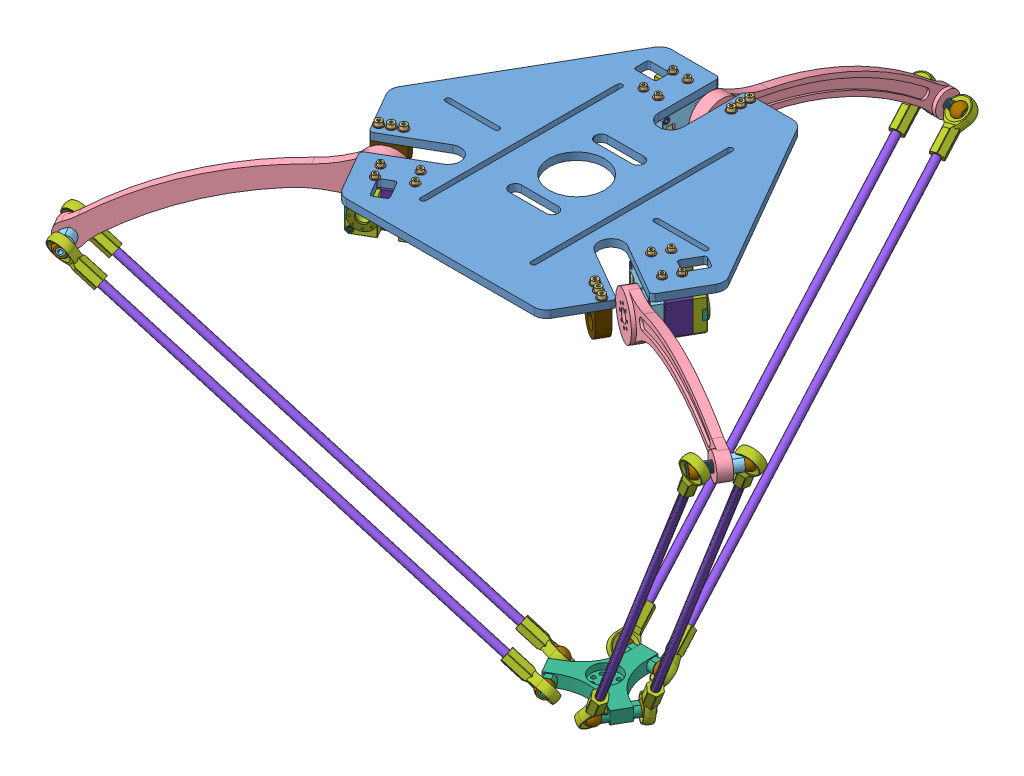
SolidWorks assembly Delta2, configuration Default. Lengths in mm.
Overall size (577.62 355.98 496.17).
140 component instances, 27 part files, 133 mates.
Components (placement in the parent):
- base_XM430-1: base_XM430 [Default] at (314.8111 1004.7421 791.2344) x (-1 0 0) z (0 1 0) size (271.39 237.71 6)
- XM430-W350-R-1: XM430-W350-R [Default] at (418.2079 990.0054 820.437) x (0 -1 0) z (-0.5 0 0.866025) size (28.5 46.5 41)
  - XM430-W350-R.step-1: XM430-W350-R.step [Default] at origin size (28.5 46.5 41)
    - Part 1.step-1: Part 1.step [Default] at (-0.4867 -0.6755 -0.5918) size (19.5 19.5 4)
    - Part 2.step-1: Part 2.step [Default] at (-0.4867 -0.6755 -0.5918) size (13.3 5.9 0.1)
    - Part 3.step-1: Part 3.step [Default] at (-0.4867 -0.6755 -0.5918) size (13.3 1.9 0.1)
    - Part 4.step-1: Part 4.step [Default] at (-0.4867 -0.6755 -0.5918) size (28.5 46.5 8.5)
    - Part 5.step-1: Part 5.step [Default] at (-0.4867 -0.6755 -0.5918) size (8 1.5 3)
    - Part 6.step-1: Part 6.step [Default] at (-0.4867 -0.6755 -0.5918) size (28.5 46.5 8.5)
    - Part 7.step-1: Part 7.step [Default] at (-0.4867 -0.6755 -0.5918) size (4 4 3.8)
    - Part 8.step-1: Part 8.step [Default] at (-0.4867 -0.6755 -0.5918) size (4 4 3.8)
    - Part 9.step-1: Part 9.step [Default] at (-0.4867 -0.6755 -0.5918) size (4 4 3.8)
    - Part 10.step-1: Part 10.step [Default] at (-0.4867 -0.6755 -0.5918) size (4 4 3.8)
    - Part 11.step-1: Part 11.step [Default] at (-0.4867 -0.6755 -0.5918) size (4 4 3.8)
    - Part 12.step-1: Part 12.step [Default] at (-0.4867 -0.6755 -0.5918) size (4 4 3.8)
    - Part 13.step-1: Part 13.step [Default] at (-0.4867 -0.6755 -0.5918) size (4 4 3.8)
    - Part 14.step-1: Part 14.step [Default] at (-0.4867 -0.6755 -0.5918) size (4 4 3.8)
    - Part 15.step-1: Part 15.step [Default] at (-0.4867 -0.6755 -0.5918) size (19.5 19.5 2)
    - Part 16.step-1: Part 16.step [Default] at (-0.4867 -0.6755 -0.5918) size (28.5 46.5 17)
- bearing_block _xm-1: bearing_block _xm [Default] at (416.3014 973.7421 876.388) x (-0.866025 0 -0.5) z (0.5 0 -0.866025) size (22.5 25 10)
- single row radial ball bearing_is-1: single row radial ball bearing_is [IS 6455 SR - 18-8-S] at (406.8111 990.4921 862.8258) x (0.85015 0.190598 0.490834) z (-0.5 0 0.866025) size (16 16 4)
- single row radial ball bearing_is-2: single row radial ball bearing_is [IS 6455 SR - 18-8-S] at (330.8111 990.4921 675.7644) x (0 0.190598 -0.981668) z (1 0 0) size (16 16 4)
- single row radial ball bearing_is-3: single row radial ball bearing_is [IS 6455 SR - 18-8-S] at (206.8112 990.4921 835.113) x (-0.85015 0.190598 0.490834) z (-0.5 0 -0.866025) size (16 16 4)
- bearing_block _xm-2: bearing_block _xm [Default] at (337.8111 973.7421 660.7644) x (0 0 1) z (-1 0 0) size (22.5 25 10)
- bearing_block _xm-3: bearing_block _xm [Default] at (190.3208 973.7421 836.5508) x (0.866025 0 -0.5) z (0.5 0 0.866025) size (22.5 25 10)
- XM430-W350-R-2: XM430-W350-R [Default] at (288.4029 990.0054 687.0889) x (0 -1 0) z (1 0 0) size (28.5 46.5 41)
  - XM430-W350-R.step-1: XM430-W350-R.step [Default] at origin size (28.5 46.5 41)
    - Part 1.step-1: Part 1.step [Default] at (-0.4867 -0.6755 -0.5918) size (19.5 19.5 4)
    - Part 2.step-1: Part 2.step [Default] at (-0.4867 -0.6755 -0.5918) size (13.3 5.9 0.1)
    - Part 3.step-1: Part 3.step [Default] at (-0.4867 -0.6755 -0.5918) size (13.3 1.9 0.1)
    - Part 4.step-1: Part 4.step [Default] at (-0.4867 -0.6755 -0.5918) size (28.5 46.5 8.5)
    - Part 5.step-1: Part 5.step [Default] at (-0.4867 -0.6755 -0.5918) size (8 1.5 3)
    - Part 6.step-1: Part 6.step [Default] at (-0.4867 -0.6755 -0.5918) size (28.5 46.5 8.5)
    - Part 7.step-1: Part 7.step [Default] at (-0.4867 -0.6755 -0.5918) size (4 4 3.8)
    - Part 8.step-1: Part 8.step [Default] at (-0.4867 -0.6755 -0.5918) size (4 4 3.8)
    - Part 9.step-1: Part 9.step [Default] at (-0.4867 -0.6755 -0.5918) size (4 4 3.8)
    - Part 10.step-1: Part 10.step [Default] at (-0.4867 -0.6755 -0.5918) size (4 4 3.8)
    - Part 11.step-1: Part 11.step [Default] at (-0.4867 -0.6755 -0.5918) size (4 4 3.8)
    - Part 12.step-1: Part 12.step [Default] at (-0.4867 -0.6755 -0.5918) size (4 4 3.8)
    - Part 13.step-1: Part 13.step [Default] at (-0.4867 -0.6755 -0.5918) size (4 4 3.8)
    - Part 14.step-1: Part 14.step [Default] at (-0.4867 -0.6755 -0.5918) size (4 4 3.8)
    - Part 15.step-1: Part 15.step [Default] at (-0.4867 -0.6755 -0.5918) size (19.5 19.5 2)
    - Part 16.step-1: Part 16.step [Default] at (-0.4867 -0.6755 -0.5918) size (28.5 46.5 17)
- XM430-W350-R-3: XM430-W350-R [Default] at (237.8225 990.0054 866.1773) x (0 -1 0) z (-0.5 0 -0.866025) size (28.5 46.5 41)
  - XM430-W350-R.step-1: XM430-W350-R.step [Default] at origin size (28.5 46.5 41)
    - Part 1.step-1: Part 1.step [Default] at (-0.4867 -0.6755 -0.5918) size (19.5 19.5 4)
    - Part 2.step-1: Part 2.step [Default] at (-0.4867 -0.6755 -0.5918) size (13.3 5.9 0.1)
    - Part 3.step-1: Part 3.step [Default] at (-0.4867 -0.6755 -0.5918) size (13.3 1.9 0.1)
    - Part 4.step-1: Part 4.step [Default] at (-0.4867 -0.6755 -0.5918) size (28.5 46.5 8.5)
    - Part 5.step-1: Part 5.step [Default] at (-0.4867 -0.6755 -0.5918) size (8 1.5 3)
    - Part 6.step-1: Part 6.step [Default] at (-0.4867 -0.6755 -0.5918) size (28.5 46.5 8.5)
    - Part 7.step-1: Part 7.step [Default] at (-0.4867 -0.6755 -0.5918) size (4 4 3.8)
    - Part 8.step-1: Part 8.step [Default] at (-0.4867 -0.6755 -0.5918) size (4 4 3.8)
    - Part 9.step-1: Part 9.step [Default] at (-0.4867 -0.6755 -0.5918) size (4 4 3.8)
    - Part 10.step-1: Part 10.step [Default] at (-0.4867 -0.6755 -0.5918) size (4 4 3.8)
    - Part 11.step-1: Part 11.step [Default] at (-0.4867 -0.6755 -0.5918) size (4 4 3.8)
    - Part 12.step-1: Part 12.step [Default] at (-0.4867 -0.6755 -0.5918) size (4 4 3.8)
    - Part 13.step-1: Part 13.step [Default] at (-0.4867 -0.6755 -0.5918) size (4 4 3.8)
    - Part 14.step-1: Part 14.step [Default] at (-0.4867 -0.6755 -0.5918) size (4 4 3.8)
    - Part 15.step-1: Part 15.step [Default] at (-0.4867 -0.6755 -0.5918) size (19.5 19.5 2)
    - Part 16.step-1: Part 16.step [Default] at (-0.4867 -0.6755 -0.5918) size (28.5 46.5 17)
- plain washer (type a)_is-1: plain washer (type a)_is [IS 2016 A- 3.4] at (199.316 1010.7421 837.1309) x (-0.701639 0 0.712533) z (0.712533 0 0.701639) size (7 0.5 7)
- plain washer (type a)_is-2: plain washer (type a)_is [IS 2016 A- 3.4] at (205.8112 1010.7421 833.3809) x (-0.554786 0 0.831993) z (0.831993 0 0.554786) size (7 0.5 7)
- plain washer (type a)_is-4: plain washer (type a)_is [IS 2016 A- 3.4] at (212.3063 1010.7421 829.6309) x (-0.362387 0 0.932028) z (0.932028 0 0.362387) size (7 0.5 7)
- plain washer (type a)_is-8: plain washer (type a)_is [IS 2016 A- 3.4] at (399.3159 1010.7421 860.8079) x (-0.133791 0 0.99101) z (0.99101 0 0.133791) size (7 0.5 7)
- plain washer (type a)_is-11: plain washer (type a)_is [IS 2016 A- 3.4] at (412.3063 1010.7421 868.3079) x (0.106727 0 0.994288) z (0.994288 0 -0.106727) size (7 0.5 7)
- plain washer (type a)_is-13: plain washer (type a)_is [IS 2016 A- 3.4] at (405.8111 1010.7421 864.5579) x (0.327312 0 0.944916) z (0.944916 0 -0.327312) size (7 0.5 7)
- plain washer (type a)_is-15: plain washer (type a)_is [IS 2016 A- 3.4] at (332.8111 1010.7421 668.2644) x (0.502717 0 0.864451) z (0.864451 0 -0.502717) size (7 0.5 7)
- plain washer (type a)_is-17: plain washer (type a)_is [IS 2016 A- 3.4] at (332.8111 1010.7421 675.7644) x (0.623048 0 0.782184) z (0.782184 0 -0.623048) size (7 0.5 7)
- plain washer (type a)_is-19: plain washer (type a)_is [IS 2016 A- 3.4] at (332.8111 1010.7421 683.2644) x (0.69089 0 0.72296) z (0.72296 0 -0.69089) size (7 0.5 7)
- socket head cap screw_is-1: socket head cap screw_is [IS 2269 - M3 x 10-N] at (199.316 1014.2421 837.1309) x (0 -1 0) z (0.966494 0 -0.25669) size (13 5.5 5.5)
- socket head cap screw_is-2: socket head cap screw_is [IS 2269 - M3 x 10-N] at (205.8112 1014.2421 833.3809) x (0 -1 0) z (0.900802 0 -0.434231) size (13 5.5 5.5)
- socket head cap screw_is-4: socket head cap screw_is [IS 2269 - M3 x 10-N] at (212.3063 1014.2421 829.6309) x (0 -1 0) z (0.786013 0 -0.61821) size (13 5.5 5.5)
- socket head cap screw_is-6: socket head cap screw_is [IS 2269 - M3 x 10-N] at (332.8111 1014.2421 668.2644) x (0 -1 0) z (0.619181 0 -0.785248) size (13 5.5 5.5)
- socket head cap screw_is-8: socket head cap screw_is [IS 2269 - M3 x 10-N] at (332.8111 1014.2421 675.7644) x (0 -1 0) z (0.413756 0 -0.910388) size (13 5.5 5.5)
- socket head cap screw_is-10: socket head cap screw_is [IS 2269 - M3 x 10-N] at (332.8111 1014.2421 683.2644) x (0 -1 0) z (0.198717 0 -0.980057) size (13 5.5 5.5)
- socket head cap screw_is-12: socket head cap screw_is [IS 2269 - M3 x 10-N] at (412.3063 1014.2421 868.3079) x (0 -1 0) z (0.006767 0 -0.999977) size (13 5.5 5.5)
- socket head cap screw_is-14: socket head cap screw_is [IS 2269 - M3 x 10-N] at (405.8111 1014.2421 864.5579) x (0 -1 0) z (-0.138678 0 -0.990337) size (13 5.5 5.5)
- socket head cap screw_is-16: socket head cap screw_is [IS 2269 - M3 x 10-N] at (399.3159 1014.2421 860.8079) x (0 -1 0) z (-0.227212 0 -0.973845) size (13 5.5 5.5)
- plain washer (type a)_is-21: plain washer (type a)_is [IS 2016 A- 2.9] at (293.8111 1010.7421 679.7644) x (0.656619 0 0.754222) z (0.754222 0 -0.656619) size (6.5 0.5 6.5)
- plain washer (type a)_is-25: plain washer (type a)_is [IS 2016 A- 2.9] at (281.8111 1010.7421 679.7644) x (0.786991 0 0.616965) z (0.616965 0 -0.786991) size (6.5 0.5 6.5)
- plain washer (type a)_is-27: plain washer (type a)_is [IS 2016 A- 2.9] at (293.8111 1010.7421 703.7644) x (0.901488 0 0.432805) z (0.432805 0 -0.901488) size (6.5 0.5 6.5)
- plain washer (type a)_is-32: plain washer (type a)_is [IS 2016 A- 2.9] at (281.8111 1010.7421 703.7644) x (0.977829 0 0.209406) z (0.209406 0 -0.977829) size (6.5 0.5 6.5)
- plain washer (type a)_is-34: plain washer (type a)_is [IS 2016 A- 2.9] at (234.7753 1010.7421 875.5482) x (0.140812 0 -0.990036) z (-0.990036 0 -0.140812) size (6.5 0.5 6.5)
- plain washer (type a)_is-35: plain washer (type a)_is [IS 2016 A- 2.9] at (427.847 1010.7421 818.3906) x (-0.927803 0 0.373071) z (0.373071 0 0.927803) size (6.5 0.5 6.5)
- plain washer (type a)_is-36: plain washer (type a)_is [IS 2016 A- 2.9] at (228.7753 1010.7421 865.1559) x (0.324866 0 -0.94576) z (-0.94576 0 -0.324866) size (6.5 0.5 6.5)
- plain washer (type a)_is-37: plain washer (type a)_is [IS 2016 A- 2.9] at (421.847 1010.7421 828.7829) x (-0.981485 0 0.191538) z (0.191538 0 0.981485) size (6.5 0.5 6.5)
- plain washer (type a)_is-38: plain washer (type a)_is [IS 2016 A- 2.9] at (255.5599 1010.7421 863.5482) x (-0.307563 0 -0.951528) z (-0.951528 0 0.307563) size (6.5 0.5 6.5)
- plain washer (type a)_is-39: plain washer (type a)_is [IS 2016 A- 2.9] at (407.0624 1010.7421 806.3906) x (-0.670266 0 0.742121) z (0.742121 0 0.670266) size (6.5 0.5 6.5)
- plain washer (type a)_is-40: plain washer (type a)_is [IS 2016 A- 2.9] at (249.5599 1010.7421 853.1559) x (-0.075924 0 -0.997114) z (-0.997114 0 0.075924) size (6.5 0.5 6.5)
- plain washer (type a)_is-41: plain washer (type a)_is [IS 2016 A- 2.9] at (401.0624 1010.7421 816.7829) x (-0.825564 0 0.564309) z (0.564309 0 0.825564) size (6.5 0.5 6.5)
- socket head cap screw_is-38: socket head cap screw_is [IS 2269 - M2.5 x 8-N] at (293.8111 1013.7421 679.7644) x (0 -1 0) z (0.760684 0 -0.649123) size (10.5 4.5 4.5)
- socket head cap screw_is-39: socket head cap screw_is [IS 2269 - M2.5 x 8-N] at (281.8111 1013.7421 679.7644) x (0 -1 0) z (0.624723 0 -0.780846) size (10.5 4.5 4.5)
- socket head cap screw_is-41: socket head cap screw_is [IS 2269 - M2.5 x 8-N] at (293.8111 1013.7421 703.7644) x (0 -1 0) z (0.441705 0 -0.89716) size (10.5 4.5 4.5)
- socket head cap screw_is-43: socket head cap screw_is [IS 2269 - M2.5 x 8-N] at (281.8111 1013.7421 703.7644) x (0 -1 0) z (0.219073 0 -0.975708) size (10.5 4.5 4.5)
- socket head cap screw_is-45: socket head cap screw_is [IS 2269 - M2.5 x 8-N] at (228.7753 1013.7421 865.1559) x (0 -1 0) z (-0.942499 0 -0.33421) size (10.5 4.5 4.5)
- socket head cap screw_is-46: socket head cap screw_is [IS 2269 - M2.5 x 8-N] at (421.847 1013.7421 828.7829) x (0 -1 0) z (0.181815 0 0.983333) size (10.5 4.5 4.5)
- socket head cap screw_is-47: socket head cap screw_is [IS 2269 - M2.5 x 8-N] at (234.7753 1013.7421 875.5482) x (0 -1 0) z (-0.988594 0 -0.150603) size (10.5 4.5 4.5)
- socket head cap screw_is-48: socket head cap screw_is [IS 2269 - M2.5 x 8-N] at (427.847 1013.7421 818.3906) x (0 -1 0) z (0.363871 0 0.931449) size (10.5 4.5 4.5)
- socket head cap screw_is-49: socket head cap screw_is [IS 2269 - M2.5 x 8-N] at (255.5599 1013.7421 863.5482) x (0 -1 0) z (-0.954525 0 0.298131) size (10.5 4.5 4.5)
- socket head cap screw_is-50: socket head cap screw_is [IS 2269 - M2.5 x 8-N] at (407.0624 1013.7421 806.3906) x (0 -1 0) z (0.735452 0 0.677577) size (10.5 4.5 4.5)
- socket head cap screw_is-51: socket head cap screw_is [IS 2269 - M2.5 x 8-N] at (249.5599 1013.7421 853.1559) x (0 -1 0) z (-0.997816 0 0.066052) size (10.5 4.5 4.5)
- socket head cap screw_is-52: socket head cap screw_is [IS 2269 - M2.5 x 8-N] at (401.0624 1013.7421 816.7829) x (0 -1 0) z (0.556111 0 0.831108) size (10.5 4.5 4.5)
- link1-1: link1 [Default] at (418.3111 990.4921 842.9072) x (0.857298 0.141609 0.494961) z (-0.5 0 0.866025) size (227.5 42.75 10)
- link1-2: link1 [Default] at (307.8111 990.4921 675.7644) x (0 -0.393866 -0.919168) z (1 0 0) size (227.5 42.75 10)
- link1-3: link1 [Default] at (218.3112 990.4921 855.0316) x (-0.80505 -0.36859 0.464796) z (-0.5 0 -0.866025) size (227.5 42.75 10)
- custom_pin-1: custom_pin [Default] at (323.8111 912.1088 491.7643) x (0 0.588093 0.808793) z (-1 0 0) size (12 10.5 42)
- custom_pin-2: custom_pin [Default] at (49.1661 917.1684 934.2123) x (0.762742 0.473604 -0.440369) z (0.5 0 0.866025) size (12 10.5 42)
- custom_pin-3: custom_pin [Default] at (581.7183 1019.2334 955.7257) x (-0.86532 0.040344 -0.499593) z (0.5 0 -0.866025) size (12 10.5 42)
- end_effector_assembly-1: end_effector_assembly [Default] at (374.6664 654.2453 825.2104) x (-0.560777 -0.060135 0.82578) z (-0.826518 0.099627 -0.554024) size (80.52 17.97 73.66)
- KCRM-06-01-1: KCRM-06-01 [Default] at (335.3363 721.3364 868.7926) x (-0.607559 -0.609042 -0.509844) z (-0.129591 -0.557287 0.820144) size (20 40 10)
- KCRM-06-01-2: KCRM-06-01 [Default] at (86.9251 900.2377 951.1043) x (0.620597 0.729976 0.286345) z (0.027943 -0.385533 0.922271) size (20 40 10)
- lower_link-2: lower_link [Default] at (348.2662 712.0245 864.5082) x (0.620597 0.729976 0.286345) z (0.027943 -0.385533 0.922271) size (6 350 6)
- KCRM-06 -02-1: KCRM-06 -02 [Default] at (358.8452 704.4057 861.0028) x (0.156369 0.983564 -0.09028) z (0.5 0 0.866025) size (12.7 12.7 9)
- KCRM-06 -02-2: KCRM-06 -02 [Default] at (63.4161 917.1684 958.894) x (0.860886 -0.108782 -0.497033) z (0.5 0 0.866025) size (12.7 12.7 9)
- KCRM-06 -02-6: KCRM-06 -02 [Default] at (579.4683 1019.2334 959.6228) x (0.829488 -0.287402 0.478905) z (-0.5 0 0.866025) size (12.7 12.7 9)
- KCRM-06 -02-7: KCRM-06 -02 [Default] at (397.0221 704.4057 861.0028) x (-0.113028 0.991447 -0.065257) z (0.5 0 -0.866025) size (12.7 12.7 9)
- lower_link-8: lower_link [Default] at (403.5553 715.6794 864.5343) x (-0.840269 0.359936 0.405455) z (-0.244434 0.416024 -0.875886) size (6 350 6)
- KCRM-06-01-9: KCRM-06-01 [Default] at (564.9501 994.1808 951.775) x (0.874111 -0.475503 -0.099133) z (-0.041603 -0.276634 0.960074) size (20 40 10)
- KCRM-06-01-10: KCRM-06-01 [Default] at (411.5404 729.4583 868.8506) x (-0.366792 -0.077836 0.927041) z (0.794521 -0.544584 0.268634) size (20 40 10)
- KCRM-06 -02-8: KCRM-06 -02 [Default] at (328.3111 912.1088 491.7643) x (0 0.033864 -0.999426) z (1 0 0) size (12.7 12.7 9)
- KCRM-06 -02-9: KCRM-06 -02 [Default] at (394.4337 704.4057 799.3618) x (0 0.812147 0.583453) z (1 0 0) size (12.7 12.7 9)
- lower_link-9: lower_link [Default] at (392.0659 711.8434 788.3471) x (0.980998 0.167633 -0.097687) z (-0.082954 0.817538 0.569869) size (6 350 6)
- KCRM-06-01-11: KCRM-06-01 [Default] at (333.5729 895.5807 516.2415) x (0.980998 0.167633 -0.097687) z (-0.082954 0.817538 0.569869) size (20 40 10)
- KCRM-06-01-12: KCRM-06-01 [Default] at (389.1719 720.9338 774.8846) x (-0.789881 -0.57343 -0.217408) z (-0.587645 0.606339 0.535749) size (20 40 10)
- KCRM-06 -02-10: KCRM-06 -02 [Default] at (595.9683 1019.2334 931.0439) x (0.847524 -0.2056 0.489318) z (-0.5 0 0.866025) size (12.7 12.7 9)
- KCRM-06 -02-11: KCRM-06 -02 [Default] at (413.5221 704.4057 832.424) x (-0.484483 0.828876 -0.279716) z (0.5 0 -0.866025) size (12.7 12.7 9)
- lower_link-10: lower_link [Default] at (420.0553 715.6794 835.9555) x (0.866547 -0.415611 -0.276339) z (0.122047 -0.360413 0.924774) size (6 350 6)
- KCRM-06-01-13: KCRM-06-01 [Default] at (581.4501 994.1808 923.1962) x (0.866547 -0.415611 -0.276339) z (0.122047 -0.360413 0.924774) size (20 40 10)
- KCRM-06-01-14: KCRM-06-01 [Default] at (428.0404 729.4583 840.2717) x (-0.649113 0.543036 -0.532695) z (-0.5869 0.087991 0.804864) size (20 40 10)
- KCRM-06 -02-12: KCRM-06 -02 [Default] at (46.9161 917.1684 930.3152) x (0.860886 -0.108782 -0.497033) z (0.5 0 0.866025) size (12.7 12.7 9)
- KCRM-06 -02-13: KCRM-06 -02 [Default] at (342.3452 704.4057 832.424) x (-0.379043 -0.89913 0.218841) z (-0.5 0 -0.866025) size (12.7 12.7 9)
- lower_link-11: lower_link [Default] at (331.7662 712.0245 835.9294) x (0.614002 0.767175 0.185591) z (0.094464 -0.304865 0.947699) size (6 350 6)
- KCRM-06-01-15: KCRM-06-01 [Default] at (70.4251 900.2377 922.5254) x (0.614002 0.767175 0.185591) z (0.094464 -0.304865 0.947699) size (20 40 10)
- KCRM-06-01-16: KCRM-06-01 [Default] at (318.8363 721.3364 840.2137) x (-0.56569 -0.475511 -0.673709) z (-0.256742 -0.674826 0.691877) size (20 40 10)
- KCRM-06 -02-14: KCRM-06 -02 [Default] at (295.3111 912.1088 491.7643) x (0 0.033842 -0.999427) z (1 0 0) size (12.7 12.7 9)
- KCRM-06 -02-15: KCRM-06 -02 [Default] at (361.4337 704.4057 799.3618) x (0 -0.943359 -0.331773) z (1 0 0) size (12.7 12.7 9)
- lower_link-12: lower_link [Default] at (359.0659 711.8434 788.3471) x (0.983235 0.140001 -0.116826) z (-0.049865 0.82272 0.566255) size (6 350 6)
- KCRM-06-01-17: KCRM-06-01 [Default] at (300.5729 895.5807 516.2415) x (0.983235 0.140001 -0.116826) z (-0.049865 0.82272 0.566255) size (20 40 10)
- KCRM-06-01-18: KCRM-06-01 [Default] at (356.1719 720.9338 774.8846) x (0.627825 -0.575779 -0.523751) z (-0.758336 -0.604109 -0.244905) size (20 40 10)
Mates (geometry in assembly coordinates):
- Coincident3: coincident anti-aligned: plane of base_XM430-1 through (314.8111 1004.7421 791.2344) normal (0 -1 0); plane of XM430-W350-R-1/XM430-W350-R.step-1/Part 16.step-1 through (442.3039 1004.7421 823.8505) normal (0 1 0)
- Concentric3: concentric anti-aligned: cylinder of base_XM430-1 through (407.0624 1000.7421 806.3906) axis (0 1 0) radius 1.6; cylinder of XM430-W350-R-1/XM430-W350-R.step-1/Part 16.step-1 through (407.0624 1001.7421 806.3906) axis (0 -1 0) radius 1
- Concentric4: concentric anti-aligned: cylinder of base_XM430-1 through (421.847 1000.7421 828.7829) axis (0 1 0) radius 1.6; cylinder of XM430-W350-R-1/XM430-W350-R.step-1/Part 16.step-1 through (421.847 1001.7421 828.7829) axis (0 -1 0) radius 1
- Concentric5: concentric aligned: cylinder of base_XM430-1 through (405.8111 1000.7421 864.5579) axis (0 1 0) radius 1.1; cylinder of bearing_block _xm-1 through (405.8111 1004.7421 864.5579) axis (0 1 0) radius 1.25
- Coincident4: coincident anti-aligned: plane of base_XM430-1 through (314.8111 1004.7421 791.2344) normal (0 -1 0); plane of bearing_block _xm-1 through (393.5683 1004.7421 863.263) normal (0 1 0)
- Concentric6: concentric aligned: cylinder of base_XM430-1 through (399.3159 1000.7421 860.8079) axis (0 1 0) radius 1.1; cylinder of bearing_block _xm-1 through (399.3159 1004.7421 860.8079) axis (0 1 0) radius 1.25
- Concentric7: concentric anti-aligned: cylinder of bearing_block _xm-1 through (405.8111 990.4921 864.5579) axis (0.5 0 -0.866025) radius 8; cylinder of single row radial ball bearing_is-1 through (381.6153 990.4921 906.4662) axis (-0.5 0 0.866025) radius 8
- Coincident5: coincident anti-aligned: plane of bearing_block _xm-1 through (405.8111 990.4921 864.5579) normal (0.5 0 -0.866025); plane of single row radial ball bearing_is-1 through (404.4906 998.3454 863.7955) normal (-0.5 0 0.866025)
- Concentric8: concentric anti-aligned: cylinder of base_XM430-1 through (199.316 1000.7421 837.1309) axis (0 1 0) radius 1.1; cylinder of plain washer (type a)_is-1 through (199.316 1010.7421 837.1309) axis (0 -1 0) radius 1.7
- Coincident6: coincident anti-aligned: plane of base_XM430-1 through (314.8111 1010.7421 791.2344) normal (0 1 0); plane of plain washer (type a)_is-1 through (198.1232 1010.7421 838.3422) normal (0 -1 0)
- Concentric9: concentric anti-aligned: cylinder of base_XM430-1 through (205.8112 1000.7421 833.3809) axis (0 1 0) radius 1.1; cylinder of plain washer (type a)_is-2 through (205.8112 1010.7421 833.3809) axis (0 -1 0) radius 1.7
- Coincident7: coincident anti-aligned: plane of base_XM430-1 through (314.8111 1010.7421 791.2344) normal (0 1 0); plane of plain washer (type a)_is-2 through (204.868 1010.7421 834.7953) normal (0 -1 0)
- Concentric10: concentric anti-aligned: cylinder of base_XM430-1 through (212.3063 1000.7421 829.6309) axis (0 1 0) radius 1.1; cylinder of plain washer (type a)_is-4 through (212.3063 1010.7421 829.6309) axis (0 -1 0) radius 1.7
- Coincident8: coincident anti-aligned: plane of base_XM430-1 through (314.8111 1010.7421 791.2344) normal (0 1 0); plane of plain washer (type a)_is-4 through (211.6903 1010.7421 831.2154) normal (0 -1 0)
- Concentric12: concentric anti-aligned: cylinder of base_XM430-1 through (399.3159 1000.7421 860.8079) axis (0 1 0) radius 1.1; cylinder of plain washer (type a)_is-8 through (399.3159 1010.7421 860.8079) axis (0 -1 0) radius 1.7
- Coincident10: coincident anti-aligned: plane of base_XM430-1 through (314.8111 1010.7421 791.2344) normal (0 1 0); plane of plain washer (type a)_is-8 through (399.0884 1010.7421 862.4926) normal (0 -1 0)
- Concentric13: concentric anti-aligned: cylinder of base_XM430-1 through (412.3063 1000.7421 868.3079) axis (0 1 0) radius 1.1; cylinder of plain washer (type a)_is-11 through (412.3063 1010.7421 868.3079) axis (0 -1 0) radius 1.7
- Coincident11: coincident anti-aligned: plane of base_XM430-1 through (314.8111 1010.7421 791.2344) normal (0 1 0); plane of plain washer (type a)_is-11 through (412.4877 1010.7421 869.9981) normal (0 -1 0)
- Concentric14: concentric anti-aligned: cylinder of base_XM430-1 through (405.8111 1000.7421 864.5579) axis (0 1 0) radius 1.1; cylinder of plain washer (type a)_is-13 through (405.8111 1010.7421 864.5579) axis (0 -1 0) radius 1.7
- Coincident12: coincident anti-aligned: plane of base_XM430-1 through (314.8111 1010.7421 791.2344) normal (0 1 0); plane of plain washer (type a)_is-13 through (406.3675 1010.7421 866.1642) normal (0 -1 0)
- Concentric15: concentric anti-aligned: cylinder of base_XM430-1 through (332.8111 1000.7421 668.2644) axis (0 1 0) radius 1.1; cylinder of plain washer (type a)_is-15 through (332.8111 1010.7421 668.2644) axis (0 -1 0) radius 1.7
- Coincident13: coincident anti-aligned: plane of base_XM430-1 through (314.8111 1010.7421 791.2344) normal (0 1 0); plane of plain washer (type a)_is-15 through (333.6657 1010.7421 669.734) normal (0 -1 0)
- Concentric16: concentric anti-aligned: cylinder of base_XM430-1 through (332.8111 1000.7421 675.7644) axis (0 1 0) radius 1.1; cylinder of plain washer (type a)_is-17 through (332.8111 1010.7421 675.7644) axis (0 -1 0) radius 1.7
- Coincident14: coincident anti-aligned: plane of base_XM430-1 through (314.8111 1010.7421 791.2344) normal (0 1 0); plane of plain washer (type a)_is-17 through (333.8703 1010.7421 677.0941) normal (0 -1 0)
- Concentric17: concentric anti-aligned: cylinder of base_XM430-1 through (332.8111 1000.7421 683.2644) axis (0 1 0) radius 1.1; cylinder of plain washer (type a)_is-19 through (332.8111 1010.7421 683.2644) axis (0 -1 0) radius 1.7
- Coincident15: coincident anti-aligned: plane of base_XM430-1 through (314.8111 1010.7421 791.2344) normal (0 1 0); plane of plain washer (type a)_is-19 through (333.9856 1010.7421 684.4934) normal (0 -1 0)
- Concentric19: concentric aligned: cylinder of base_XM430-1 through (199.316 1000.7421 837.1309) axis (0 1 0) radius 1.1; cylinder of socket head cap screw_is-1 through (199.316 1014.2421 837.1309) axis (0 1 0) radius 1.5
- Coincident16: coincident anti-aligned: plane of plain washer (type a)_is-1 through (198.1232 1011.2421 838.3422) normal (0 1 0); plane of socket head cap screw_is-1 through (198.6101 1011.2421 834.4731) normal (0 -1 0)
- Concentric20: concentric aligned: cylinder of base_XM430-1 through (205.8112 1000.7421 833.3809) axis (0 1 0) radius 1.1; cylinder of socket head cap screw_is-2 through (205.8112 1014.2421 833.3809) axis (0 1 0) radius 1.5
- Coincident17: coincident anti-aligned: plane of plain washer (type a)_is-2 through (204.868 1011.2421 834.7953) normal (0 1 0); plane of socket head cap screw_is-2 through (204.617 1011.2421 830.9037) normal (0 -1 0)
- Concentric21: concentric aligned: cylinder of base_XM430-1 through (212.3063 1000.7421 829.6309) axis (0 1 0) radius 1.1; cylinder of socket head cap screw_is-4 through (212.3063 1014.2421 829.6309) axis (0 1 0) radius 1.5
- Coincident18: coincident anti-aligned: plane of plain washer (type a)_is-4 through (211.6903 1011.2421 831.2154) normal (0 1 0); plane of socket head cap screw_is-4 through (210.6063 1011.2421 827.4694) normal (0 -1 0)
- Concentric22: concentric aligned: cylinder of base_XM430-1 through (332.8111 1000.7421 668.2644) axis (0 1 0) radius 1.1; cylinder of socket head cap screw_is-6 through (332.8111 1014.2421 668.2644) axis (0 1 0) radius 1.5
- Coincident19: coincident anti-aligned: plane of plain washer (type a)_is-15 through (333.6657 1011.2421 669.734) normal (0 1 0); plane of socket head cap screw_is-6 through (330.6517 1011.2421 666.5617) normal (0 -1 0)
- Concentric23: concentric aligned: cylinder of base_XM430-1 through (332.8111 1000.7421 675.7644) axis (0 1 0) radius 1.1; cylinder of socket head cap screw_is-8 through (332.8111 1014.2421 675.7644) axis (0 1 0) radius 1.5
- Coincident20: coincident anti-aligned: plane of plain washer (type a)_is-17 through (333.8703 1011.2421 677.0941) normal (0 1 0); plane of socket head cap screw_is-8 through (330.3075 1011.2421 674.6266) normal (0 -1 0)
- Concentric24: concentric aligned: cylinder of base_XM430-1 through (332.8111 1000.7421 683.2644) axis (0 1 0) radius 1.1; cylinder of socket head cap screw_is-10 through (332.8111 1014.2421 683.2644) axis (0 1 0) radius 1.5
- Coincident21: coincident anti-aligned: plane of plain washer (type a)_is-19 through (333.9856 1011.2421 684.4934) normal (0 1 0); plane of socket head cap screw_is-10 through (330.116 1011.2421 682.7179) normal (0 -1 0)
- Concentric25: concentric aligned: cylinder of base_XM430-1 through (412.3063 1000.7421 868.3079) axis (0 1 0) radius 1.1; cylinder of socket head cap screw_is-12 through (412.3063 1014.2421 868.3079) axis (0 1 0) radius 1.5
- Coincident22: coincident anti-aligned: plane of plain washer (type a)_is-11 through (412.4877 1011.2421 869.9981) normal (0 1 0); plane of socket head cap screw_is-12 through (409.5563 1011.2421 868.2892) normal (0 -1 0)
- Concentric26: concentric aligned: cylinder of base_XM430-1 through (405.8111 1000.7421 864.5579) axis (0 1 0) radius 1.1; cylinder of socket head cap screw_is-14 through (405.8111 1014.2421 864.5579) axis (0 1 0) radius 1.5
- Coincident23: coincident anti-aligned: plane of plain washer (type a)_is-13 through (406.3675 1011.2421 866.1642) normal (0 1 0); plane of socket head cap screw_is-14 through (403.0876 1011.2421 864.9392) normal (0 -1 0)
- Concentric27: concentric aligned: cylinder of base_XM430-1 through (399.3159 1000.7421 860.8079) axis (0 1 0) radius 1.1; cylinder of socket head cap screw_is-16 through (399.3159 1014.2421 860.8079) axis (0 1 0) radius 1.5
- Coincident24: coincident anti-aligned: plane of plain washer (type a)_is-8 through (399.0884 1011.2421 862.4926) normal (0 1 0); plane of socket head cap screw_is-16 through (396.6378 1011.2421 861.4327) normal (0 -1 0)
- Concentric30: concentric anti-aligned: cylinder of base_XM430-1 through (293.8111 1000.7421 679.7644) axis (0 1 0) radius 1.6; cylinder of plain washer (type a)_is-21 through (293.8111 1010.7421 679.7644) axis (0 -1 0) radius 1.45
- Coincident28: coincident anti-aligned: plane of base_XM430-1 through (314.8111 1010.7421 791.2344) normal (0 1 0); plane of plain washer (type a)_is-21 through (294.7632 1010.7421 680.858) normal (0 -1 0)
- Concentric32: concentric anti-aligned: cylinder of base_XM430-1 through (281.8111 1000.7421 679.7644) axis (0 1 0) radius 1.6; cylinder of plain washer (type a)_is-25 through (281.8111 1010.7421 679.7644) axis (0 -1 0) radius 1.45
- Coincident32: coincident anti-aligned: plane of base_XM430-1 through (314.8111 1010.7421 791.2344) normal (0 1 0); plane of plain washer (type a)_is-25 through (282.9522 1010.7421 680.659) normal (0 -1 0)
- Concentric34: concentric anti-aligned: cylinder of base_XM430-1 through (293.8111 1000.7421 703.7644) axis (0 1 0) radius 1.6; cylinder of plain washer (type a)_is-27 through (293.8111 1010.7421 703.7644) axis (0 -1 0) radius 1.45
- Coincident35: coincident anti-aligned: plane of base_XM430-1 through (314.8111 1010.7421 791.2344) normal (0 1 0); plane of plain washer (type a)_is-27 through (295.1183 1010.7421 704.392) normal (0 -1 0)
- Concentric36: concentric anti-aligned: cylinder of base_XM430-1 through (281.8111 1000.7421 703.7644) axis (0 1 0) radius 1.6; cylinder of plain washer (type a)_is-32 through (281.8111 1010.7421 703.7644) axis (0 -1 0) radius 1.45
- Coincident41: coincident anti-aligned: plane of base_XM430-1 through (314.8111 1010.7421 791.2344) normal (0 1 0); plane of plain washer (type a)_is-32 through (283.229 1010.7421 704.068) normal (0 -1 0)
- Concentric37: concentric aligned: cylinder of base_XM430-1 through (293.8111 1000.7421 679.7644) axis (0 1 0) radius 1.6; cylinder of socket head cap screw_is-38 through (293.8111 1013.7421 679.7644) axis (0 1 0) radius 1.25
- Coincident43: coincident anti-aligned: plane of plain washer (type a)_is-21 through (294.7632 1011.2421 680.858) normal (0 1 0); plane of socket head cap screw_is-38 through (292.3506 1011.2421 678.0529) normal (0 -1 0)
- Concentric38: concentric aligned: cylinder of base_XM430-1 through (281.8111 1000.7421 679.7644) axis (0 1 0) radius 1.6; cylinder of socket head cap screw_is-39 through (281.8111 1013.7421 679.7644) axis (0 1 0) radius 1.25
- Coincident44: coincident anti-aligned: plane of plain washer (type a)_is-25 through (282.9522 1011.2421 680.659) normal (0 1 0); plane of socket head cap screw_is-39 through (280.0542 1011.2421 678.3588) normal (0 -1 0)
- Concentric39: concentric aligned: cylinder of base_XM430-1 through (293.8111 1000.7421 703.7644) axis (0 1 0) radius 1.6; cylinder of socket head cap screw_is-41 through (293.8111 1013.7421 703.7644) axis (0 1 0) radius 1.25
- Coincident45: coincident anti-aligned: plane of plain washer (type a)_is-27 through (295.1183 1011.2421 704.392) normal (0 1 0); plane of socket head cap screw_is-41 through (291.7925 1011.2421 702.7706) normal (0 -1 0)
- Concentric40: concentric aligned: cylinder of base_XM430-1 through (281.8111 1000.7421 703.7644) axis (0 1 0) radius 1.6; cylinder of socket head cap screw_is-43 through (281.8111 1013.7421 703.7644) axis (0 1 0) radius 1.25
- Coincident46: coincident anti-aligned: plane of plain washer (type a)_is-32 through (283.229 1011.2421 704.068) normal (0 1 0); plane of socket head cap screw_is-43 through (279.6158 1011.2421 703.2715) normal (0 -1 0)
- Concentric41: concentric anti-aligned: cylinder of single row radial ball bearing_is-1 through (371.3798 990.4921 924.1946) axis (-0.5 0 0.866025) radius 4; cylinder of link1-1 through (413.3111 990.4921 851.5675) axis (0.5 0 -0.866025) radius 5
- Coincident47: coincident anti-aligned: plane of XM430-W350-R-1/XM430-W350-R.step-1/Part 1.step-1 through (418.3111 990.4921 842.9072) normal (-0.5 0 0.866025); plane of link1-1 through (564.5989 871.0454 927.3665) normal (0.5 0 -0.866025)
- Concentric42: concentric anti-aligned: cylinder of single row radial ball bearing_is-3 through (171.3799 990.4921 773.7442) axis (-0.5 0 -0.866025) radius 4; cylinder of link1-3 through (213.3112 990.4921 846.3713) axis (0.5 0 0.866025) radius 5
- Coincident48: coincident anti-aligned: plane of XM430-W350-R-3/XM430-W350-R.step-1/Part 1.step-1 through (218.3112 990.4921 855.0316) normal (-0.5 0 -0.866025); plane of link1-3 through (142.6904 802.9385 898.6912) normal (0.5 0 0.866025)
- Concentric43: concentric anti-aligned: cylinder of single row radial ball bearing_is-2 through (401.6737 990.4921 675.7644) axis (1 0 0) radius 4; cylinder of link1-2 through (317.8111 990.4921 675.7644) axis (-1 0 0) radius 5
- Coincident49: coincident anti-aligned: plane of XM430-W350-R-2/XM430-W350-R.step-1/Part 1.step-1 through (307.8111 990.4921 675.7644) normal (1 0 0); plane of link1-2 through (307.8111 800.6214 593.6052) normal (-1 0 0)
- Concentric44: concentric anti-aligned: cylinder of link1-2 through (317.8111 912.1088 491.7643) axis (-1 0 0) radius 4; cylinder of custom_pin-1 through (307.8111 912.1088 491.7643) axis (1 0 0) radius 4
- Coincident50: coincident anti-aligned: plane of link1-2 through (307.8111 800.6214 593.6052) normal (-1 0 0); plane of custom_pin-1 through (307.8111 912.1088 491.7643) normal (1 0 0)
- Concentric46: concentric anti-aligned: cylinder of link1-3 through (52.1661 917.1684 939.4085) axis (0.5 0 0.866025) radius 4; cylinder of custom_pin-2 through (57.1661 917.1684 948.0687) axis (-0.5 0 -0.866025) radius 4
- Coincident51: coincident anti-aligned: plane of link1-3 through (142.6904 802.9385 898.6912) normal (0.5 0 0.866025); plane of custom_pin-2 through (57.1661 917.1684 948.0687) normal (-0.5 0 -0.866025)
- Concentric47: concentric anti-aligned: cylinder of link1-1 through (584.7183 1019.2334 950.5295) axis (0.5 0 -0.866025) radius 4; cylinder of custom_pin-3 through (589.7183 1019.2334 941.8693) axis (-0.5 0 0.866025) radius 4
- Coincident52: coincident anti-aligned: plane of link1-1 through (564.5989 871.0454 927.3665) normal (0.5 0 -0.866025); plane of custom_pin-3 through (589.7183 1019.2334 941.8693) normal (-0.5 0 0.866025)
- Concentric53: concentric anti-aligned: cylinder of KCRM-06-01-2 through (86.9251 900.2377 951.1043) axis (-0.783632 0.564357 0.259658) radius 2.4585; cylinder of lower_link-2 through (73.9951 909.5496 955.3886) axis (0.783632 -0.564357 -0.259658) radius 3
- Coincident59: coincident anti-aligned: plane of KCRM-06-01-2 through (86.9251 900.2377 951.1043) normal (0.783632 -0.564357 -0.259658); plane of lower_link-2 through (86.9251 900.2377 951.1043) normal (-0.783632 0.564357 0.259658)
- Coincident60: coincident: point of KCRM-06-01-2; point of KCRM-06 -02-2
- Concentric55: concentric aligned: cylinder of KCRM-06-01-1 through (335.3363 721.3364 868.7926) axis (0.783632 -0.564357 -0.259658) radius 2.4585; cylinder of lower_link-2 through (73.9951 909.5496 955.3886) axis (0.783632 -0.564357 -0.259658) radius 3
- Coincident61: coincident anti-aligned: plane of KCRM-06-01-1 through (335.3363 721.3364 868.7926) normal (-0.783632 0.564357 0.259658); plane of lower_link-2 through (335.3363 721.3364 868.7926) normal (0.783632 -0.564357 -0.259658)
- Coincident62: coincident: sphere of KCRM-06 -02-1; unknown of KCRM-06-01-1
- Concentric56: concentric anti-aligned: cylinder of lower_link-8 through (572.9351 1007.9598 956.0913) axis (-0.483942 -0.835087 -0.261591) radius 3; cylinder of KCRM-06-01-9 through (564.9501 994.1808 951.775) axis (0.483942 0.835087 0.261591) radius 2.4585
- Coincident63: coincident anti-aligned: plane of lower_link-8 through (564.9501 994.1808 951.775) normal (0.483942 0.835087 0.261591); plane of KCRM-06-01-9 through (564.9501 994.1808 951.775) normal (-0.483942 -0.835087 -0.261591)
- Concentric57: concentric aligned: cylinder of lower_link-8 through (572.9351 1007.9598 956.0913) axis (-0.483942 -0.835087 -0.261591) radius 3; cylinder of KCRM-06-01-10 through (411.5404 729.4583 868.8506) axis (-0.483942 -0.835087 -0.261591) radius 2.4585
- Coincident64: coincident: point of KCRM-06 -02-7; point of KCRM-06-01-10
- Coincident65: coincident anti-aligned: plane of lower_link-8 through (411.5404 729.4583 868.8506) normal (-0.483942 -0.835087 -0.261591); plane of KCRM-06-01-10 through (411.5404 729.4583 868.8506) normal (0.483942 0.835087 0.261591)
- Coincident66: coincident: point of KCRM-06 -02-6; point of KCRM-06-01-9
- Concentric58: concentric anti-aligned: cylinder of lower_link-9 through (330.6789 904.6711 502.779) axis (0.175391 -0.550936 0.815909) radius 3; cylinder of KCRM-06-01-11 through (333.5729 895.5807 516.2415) axis (-0.175391 0.550936 -0.815909) radius 2.4585
- Coincident67: coincident anti-aligned: plane of lower_link-9 through (333.5729 895.5807 516.2415) normal (-0.175391 0.550936 -0.815909); plane of KCRM-06-01-11 through (333.5729 895.5807 516.2415) normal (0.175391 -0.550936 0.815909)
- Concentric59: concentric aligned: cylinder of lower_link-9 through (330.6789 904.6711 502.779) axis (0.175391 -0.550936 0.815909) radius 3; cylinder of KCRM-06-01-12 through (389.1719 720.9338 774.8846) axis (0.175391 -0.550936 0.815909) radius 2.4585
- Coincident68: coincident: point of KCRM-06 -02-9; point of KCRM-06-01-12
- Coincident69: coincident anti-aligned: plane of lower_link-9 through (389.1719 720.9338 774.8846) normal (0.175391 -0.550936 0.815909); plane of KCRM-06-01-12 through (389.1719 720.9338 774.8846) normal (-0.175391 0.550936 -0.815909)
- Coincident70: coincident: point of KCRM-06 -02-8; point of KCRM-06-01-11
- Concentric60: concentric anti-aligned: cylinder of lower_link-10 through (589.4351 1007.9598 927.5125) axis (-0.483942 -0.835087 -0.261591) radius 3; cylinder of KCRM-06-01-13 through (581.4501 994.1808 923.1962) axis (0.483942 0.835087 0.261591) radius 2.4585
- Coincident71: coincident anti-aligned: plane of lower_link-10 through (581.4501 994.1808 923.1962) normal (0.483942 0.835087 0.261591); plane of KCRM-06-01-13 through (581.4501 994.1808 923.1962) normal (-0.483942 -0.835087 -0.261591)
- Concentric61: concentric aligned: cylinder of lower_link-10 through (589.4351 1007.9598 927.5125) axis (-0.483942 -0.835087 -0.261591) radius 3; cylinder of KCRM-06-01-14 through (428.0404 729.4583 840.2717) axis (-0.483942 -0.835087 -0.261591) radius 2.4585
- Coincident72: coincident: point of KCRM-06 -02-11; point of KCRM-06-01-14
- Coincident73: coincident anti-aligned: plane of lower_link-10 through (428.0404 729.4583 840.2717) normal (-0.483942 -0.835087 -0.261591); plane of KCRM-06-01-14 through (428.0404 729.4583 840.2717) normal (0.483942 0.835087 0.261591)
- Coincident74: coincident: point of KCRM-06 -02-10; point of KCRM-06-01-13
- Concentric62: concentric anti-aligned: cylinder of lower_link-11 through (57.4951 909.5496 926.8098) axis (0.783632 -0.564357 -0.259658) radius 3; cylinder of KCRM-06-01-15 through (70.4251 900.2377 922.5254) axis (-0.783632 0.564357 0.259658) radius 2.4585
- Coincident75: coincident anti-aligned: plane of lower_link-11 through (70.4251 900.2377 922.5254) normal (-0.783632 0.564357 0.259658); plane of KCRM-06-01-15 through (70.4251 900.2377 922.5254) normal (0.783632 -0.564357 -0.259658)
- Concentric63: concentric aligned: cylinder of lower_link-11 through (57.4951 909.5496 926.8098) axis (0.783632 -0.564357 -0.259658) radius 3; cylinder of KCRM-06-01-16 through (318.8363 721.3364 840.2137) axis (0.783632 -0.564357 -0.259658) radius 2.4585
- Coincident76: coincident: point of KCRM-06 -02-13; point of KCRM-06-01-16
- Coincident77: coincident anti-aligned: plane of lower_link-11 through (318.8363 721.3364 840.2137) normal (0.783632 -0.564357 -0.259658); plane of KCRM-06-01-16 through (318.8363 721.3364 840.2137) normal (-0.783632 0.564357 0.259658)
- Coincident78: coincident: point of KCRM-06 -02-12; point of KCRM-06-01-15
- Concentric64: concentric anti-aligned: cylinder of lower_link-12 through (297.6789 904.6711 502.779) axis (0.175391 -0.550936 0.815909) radius 3; cylinder of KCRM-06-01-17 through (300.5729 895.5807 516.2415) axis (-0.175391 0.550936 -0.815909) radius 2.4585
- Coincident79: coincident anti-aligned: plane of lower_link-12 through (300.5729 895.5807 516.2415) normal (-0.175391 0.550936 -0.815909); plane of KCRM-06-01-17 through (300.5729 895.5807 516.2415) normal (0.175391 -0.550936 0.815909)
- Concentric65: concentric aligned: cylinder of lower_link-12 through (297.6789 904.6711 502.779) axis (0.175391 -0.550936 0.815909) radius 3; cylinder of KCRM-06-01-18 through (356.1719 720.9338 774.8846) axis (0.175391 -0.550936 0.815909) radius 2.4585
- Coincident80: coincident: point of KCRM-06 -02-15; point of KCRM-06-01-18
- Coincident81: coincident anti-aligned: plane of lower_link-12 through (356.1719 720.9338 774.8846) normal (0.175391 -0.550936 0.815909); plane of KCRM-06-01-18 through (356.1719 720.9338 774.8846) normal (-0.175391 0.550936 -0.815909)
- Coincident82: coincident: point of KCRM-06 -02-14; point of KCRM-06-01-17
- Concentric66: concentric anti-aligned: cylinder of end_effector_assembly-1 through (361.0952 704.4057 864.8999) axis (-0.5 0 -0.866025) radius 3; cylinder of KCRM-06 -02-1 through (356.5952 704.4057 857.1057) axis (0.5 0 0.866025) radius 3
- Concentric67: concentric anti-aligned: cylinder of custom_pin-2 through (65.6661 917.1684 962.7911) axis (-0.5 0 -0.866025) radius 3; cylinder of KCRM-06 -02-2 through (61.1661 917.1684 954.9969) axis (0.5 0 0.866025) radius 3
- Coincident83: coincident aligned: plane of end_effector_assembly-1 through (361.0952 704.4057 864.8999) normal (0.5 0 0.866025); plane of KCRM-06 -02-1 through (357.279 705.2147 867.1032) normal (0.5 0 0.866025)
- Coincident84: coincident aligned: plane of custom_pin-2 through (65.6661 917.1684 962.7911) normal (0.5 0 0.866025); plane of KCRM-06 -02-2 through (66.0882 921.622 962.5475) normal (0.5 0 0.866025)
- Concentric68: concentric aligned: cylinder of end_effector_assembly-1 through (394.7721 704.4057 864.8999) axis (0.5 0 -0.866025) radius 3; cylinder of KCRM-06 -02-7 through (394.7721 704.4057 864.8999) axis (0.5 0 -0.866025) radius 3
- Concentric69: concentric anti-aligned: cylinder of custom_pin-3 through (577.2183 1019.2334 963.5199) axis (0.5 0 -0.866025) radius 3; cylinder of KCRM-06 -02-6 through (581.7183 1019.2334 955.7257) axis (-0.5 0 0.866025) radius 3
- Coincident85: coincident aligned: plane of custom_pin-3 through (577.2183 1019.2334 963.5199) normal (-0.5 0 0.866025); plane of KCRM-06 -02-6 through (578.3334 1023.5247 964.1637) normal (-0.5 0 0.866025)
- Coincident86: coincident aligned: plane of end_effector_assembly-1 through (394.7721 704.4057 864.8999) normal (-0.5 0 0.866025); plane of KCRM-06 -02-7 through (397.348 704.7973 866.3871) normal (-0.5 0 0.866025)
- Concentric70: concentric anti-aligned: cylinder of end_effector_assembly-1 through (415.7721 704.4057 828.5269) axis (-0.5 0 0.866025) radius 3; cylinder of KCRM-06 -02-11 through (411.2721 704.4057 836.3211) axis (0.5 0 -0.866025) radius 3
- Coincident87: coincident aligned: plane of end_effector_assembly-1 through (415.7721 704.4057 828.5269) normal (0.5 0 -0.866025); plane of KCRM-06 -02-11 through (418.9882 706.9121 830.3837) normal (0.5 0 -0.866025)
- Concentric71: concentric aligned: cylinder of custom_pin-3 through (598.2183 1019.2334 927.1468) axis (-0.5 0 0.866025) radius 3; cylinder of KCRM-06 -02-10 through (598.2183 1019.2334 927.1468) axis (-0.5 0 0.866025) radius 3
- Coincident88: coincident aligned: plane of custom_pin-3 through (598.2183 1019.2334 927.1468) normal (0.5 0 -0.866025); plane of KCRM-06 -02-10 through (598.7525 1022.1693 927.4552) normal (0.5 0 -0.866025)
- Concentric72: concentric anti-aligned: cylinder of end_effector_assembly-1 through (340.0952 704.4057 828.5269) axis (0.5 0 0.866025) radius 3; cylinder of KCRM-06 -02-13 through (344.5952 704.4057 836.3211) axis (-0.5 0 -0.866025) radius 3
- Coincident89: coincident aligned: plane of end_effector_assembly-1 through (340.0952 704.4057 828.5269) normal (-0.5 0 -0.866025); plane of KCRM-06 -02-13 through (336.6066 706.3666 830.541) normal (-0.5 0 -0.866025)
- Concentric73: concentric aligned: cylinder of custom_pin-2 through (44.6661 917.1684 926.4181) axis (0.5 0 0.866025) radius 3; cylinder of KCRM-06 -02-12 through (44.6661 917.1684 926.4181) axis (0.5 0 0.866025) radius 3
- Coincident90: coincident aligned: plane of custom_pin-2 through (44.6661 917.1684 926.4181) normal (-0.5 0 -0.866025); plane of KCRM-06 -02-12 through (44.9487 920.1506 926.2549) normal (-0.5 0 -0.866025)
- Concentric74: concentric aligned: cylinder of end_effector_assembly-1 through (356.9337 704.4057 799.3618) axis (1 0 0) radius 3; cylinder of KCRM-06 -02-15 through (356.9337 704.4057 799.3618) axis (1 0 0) radius 3
- Coincident91: coincident aligned: plane of end_effector_assembly-1 through (356.9337 704.4057 799.3618) normal (-1 0 0); plane of KCRM-06 -02-15 through (356.9337 705.401 796.5317) normal (-1 0 0)
- Coincident92: coincident aligned: circle of custom_pin-1; circle of KCRM-06 -02-14
- Concentric75: concentric anti-aligned: cylinder of end_effector_assembly-1 through (398.9337 704.4057 799.3618) axis (-1 0 0) radius 3; cylinder of KCRM-06 -02-9 through (389.9337 704.4057 799.3618) axis (1 0 0) radius 3
- Concentric76: concentric anti-aligned: cylinder of custom_pin-1 through (332.8111 912.1088 491.7643) axis (-1 0 0) radius 3; cylinder of KCRM-06 -02-8 through (323.8111 912.1088 491.7643) axis (1 0 0) radius 3
- Coincident94: coincident aligned: plane of custom_pin-1 through (290.8111 912.1088 491.7643) normal (-1 0 0); plane of KCRM-06 -02-14 through (290.8111 915.107 491.8658) normal (-1 0 0)
- Coincident95: coincident aligned: plane of custom_pin-1 through (332.8111 912.1088 491.7643) normal (1 0 0); plane of KCRM-06 -02-8 through (332.8111 916.5864 491.916) normal (1 0 0)
- Parallel3: parallel anti-aligned: plane of base_XM430-1 through (314.8111 1004.7421 791.2344) normal (0 -1 0); plane of end_effector_assembly-1 through (377.9337 709.4057 830.9296) normal (0 1 0)
- Coincident98: coincident aligned: plane of end_effector_assembly-1 through (398.9337 704.4057 799.3618) normal (1 0 0); plane of KCRM-06 -02-9 through (398.9337 701.7917 803.0004) normal (1 0 0)
